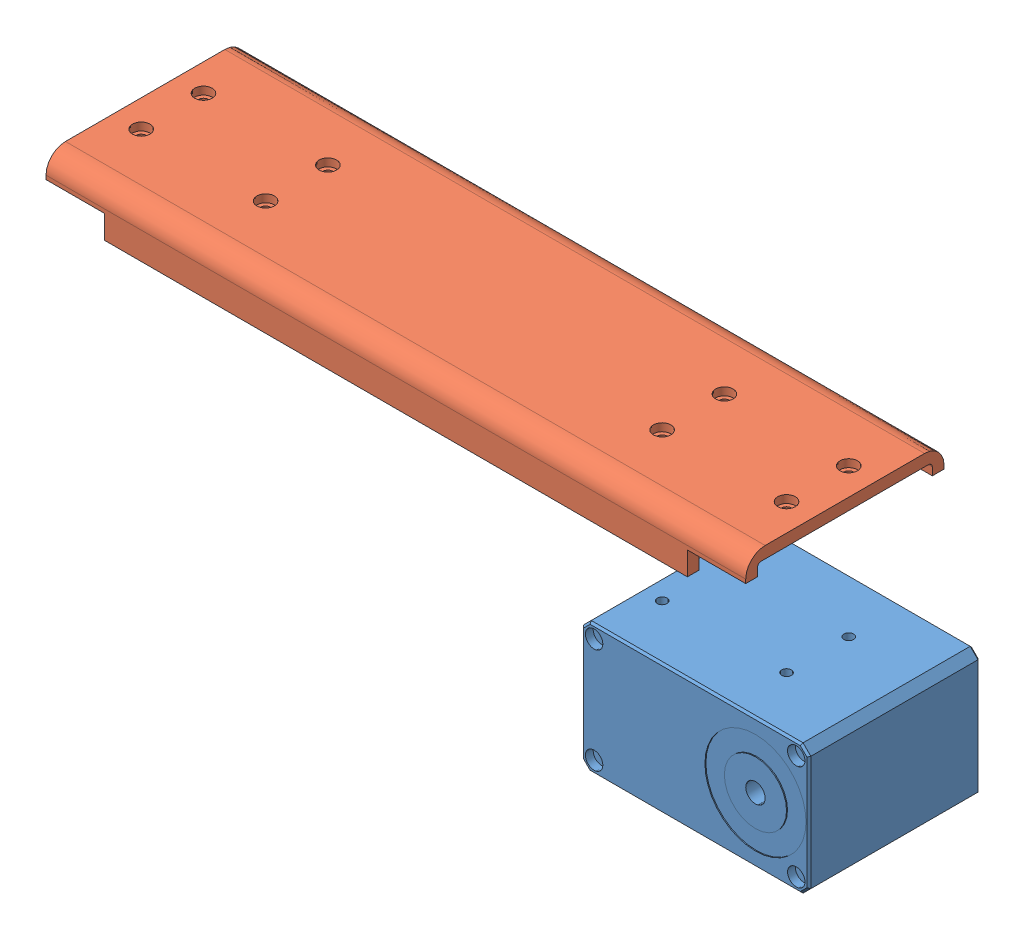
SolidWorks assembly Assem1, configuration Default. Lengths in mm.
Overall size (192.75 71.58 51).
2 component instances, 2 part files, 2 mates.
Components (placement in the parent):
- X540-1: X540 [Default] at (1.041 29.0707 34.8676) size (58.5 33.5 44)
- Thigh540540_Aluminium-1: Thigh540540_Aluminium [Default] at (-72.459 82.4049 56.8676) x (0 0 1) z (1 0 0) size (51 12 180)
Mates (geometry in assembly coordinates):
- Concentric1: concentric aligned: circle of X540-1; circle of Thigh540540_Aluminium-1
- Concentric2: concentric aligned: circle of X540-1; circle of Thigh540540_Aluminium-1
